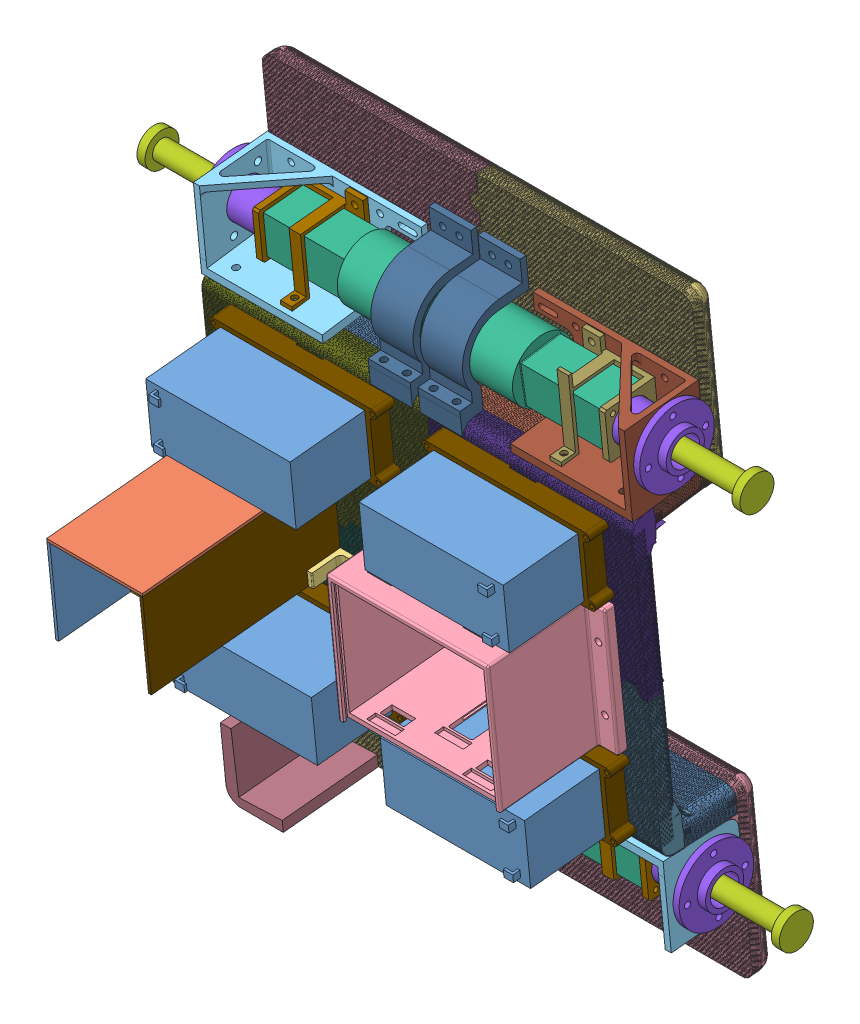
SolidWorks assembly A_B_C_subSplitParts_inserts, configuration Default. Lengths in mm.
Overall size (631 668.02 349.01).
106 component instances, 42 part files, 44 mates.
Components (placement in the parent):
- B_neo_texture_complete_55mm_1of2-1: B_neo_texture_complete_55mm_1of2 [Default] at (-505.8627 63.1056 254.1155) x (1 0 0) z (0 0.998921 0.046441) size (219.85 54.89 24)
- B_neo_texture_complete_55mm_2of2-1: B_neo_texture_complete_55mm_2of2 [Default] at (-505.8627 63.1056 254.1155) x (1 0 0) z (0 0.998921 0.046441) size (236.08 54.89 24)
- A_neo_part1-1: A_neo_part1 [Default] at (-291.5394 190.3641 320.5443) x (0 0.995122 0.098657) z (0 0.098657 -0.995122) size (187.3 234.72 36.32)
- A_neo_part1_inserts-1: A_neo_part1_inserts [Default] at (-174.6404 16.2028 208.0467) x (0 0.995122 0.098657) z (0 0.098657 -0.995122) size (187.33 225.47 36.32)
- assemblage moteur_simplifie-braquette-sol_sansPlancher-1: assemblage moteur_simplifie-braquette-sol_sansPlancher [Default] at (-882.4169 176.9564 -106.1681) x (0 0.995122 0.098657) z (1 0 0) size (163.91 86.22 311.5)
  - braquette bleu-1: braquette bleu [Default] at (-188.5719 315.838 826.9542) x (0 0 -1) z (1 0 0) size (205.75 78 138.28)
  - assemblage_moteur_pla_simplifie-1: assemblage_moteur_pla_simplifie [Default] at (-199.7546 211.4142 762.3925) x (0 0 1) z (0 1 0) size (311.5 78.45 78.45)
    - moteur_pla_simplifie-2: moteur_pla_simplifie [Default] at (-156.9384 51.1827 137.4238) size (176.5 64 64)
    - moteur_axe_pla_simplifie-1: moteur_axe_pla_simplifie [Default] at (3.5616 51.1827 137.4238) size (151 35.5 35.5)
    - front_housing_moteur_pla_simplifie-2: front_housing_moteur_pla_simplifie [Default] at (64.5616 51.1827 137.4238) x (1 0 0) z (0 0.00581 0.999983) size (60 78 78)
  - braquette gearbox-1: braquette gearbox [Default] at (-173.6322 327.188 785.9741) x (-0.000012 0 -1) z (0 -1 0) size (72.34 80.66 66.5)
  - braquette moteur- v2-1: braquette moteur- v2 [Default] at (-148.5686 348.838 605.4542) x (-1 0 0) z (0 0 -1) size (123.62 80 44)
- assemblage moteur_simplifie-braquette-sol_sansPlancher_Miroir-1: assemblage moteur_simplifie-braquette-sol_sansPlancher_Miroir [Default] at (510.9929 32.8996 -148.689) x (0 -0.99863 -0.052336) z (-1 0 0) size (180.67 88.54 311.5)
  - assemblage_moteur_pla_simplifie-1: assemblage_moteur_pla_simplifie [Default] at (-32.6554 239.0613 952.694) x (0 0 1) z (0 1 0) size (311.5 78.45 78.45)
    - moteur_pla_simplifie-2: moteur_pla_simplifie [Default] at (-156.9384 51.1827 137.4238) size (176.5 64 64)
    - moteur_axe_pla_simplifie-1: moteur_axe_pla_simplifie [Default] at (3.5616 51.1827 137.4238) size (151 35.5 35.5)
    - front_housing_moteur_pla_simplifie-2: front_housing_moteur_pla_simplifie [Default] at (64.5616 51.1827 137.4238) x (1 0 0) z (0 0.00581 0.999983) size (60 78 78)
  - braquette moteur- v2-1: braquette moteur- v2 [Default] at (18.5239 376.4853 839.7557) x (0.99917 -0.04074 0) z (0 0 1) size (123.62 80 44)
  - braquette bleue_mirroir-1: braquette bleue_mirroir [Default] at (56.9516 341.6631 1017.2557) x (0 0 -1) z (0.998921 -0.046441 0) size (167 78 87.38)
  - braquette gearbox_miroir_sansRef-1: braquette gearbox_miroir_sansRef [Default] at (70.4037 352.3999 976.2757) x (0 0 -1) z (-0.046441 -0.998921 0) size (72.34 158.52 66.5)
- Part1^A_B_C_subSplitParts_inserts-1: Part1^A_B_C_subSplitParts_inserts [Default] at (-291.5394 201.016 213.1012) x (0 -0.995122 -0.098657) z (0 -0.098657 0.995122) size (74.3 58.51 100) (virtual)
- C_assy_half_fix_part2of4-1: C_assy_half_fix_part2of4 [Default] at (-291.6733 128.4726 271.3664) x (0 0.995122 0.098657) z (1 0 0) size (163.15 37.28 239.16)
- C_assy_half_fix_part1of4-1: C_assy_half_fix_part1of4 [Default] at (-291.6733 128.2733 271.3467) x (0 0.995122 0.098657) z (1 0 0) size (163.15 37.29 220.95)
- C_assy_fix_half_hexCut_3of4-2: C_assy_fix_half_hexCut_3of4 [Default] at (-446.4822 196.3733 300.9272) x (0 -0.995122 -0.098657) z (-1 0 0) size (172.5 37.28 239.16)
- C_assy_fix_half_hexCut_4of4-2: C_assy_fix_half_hexCut_4of4 [Default] at (-446.4822 196.5726 300.947) x (0 -0.995122 -0.098657) z (-1 0 0) size (172.46 37.29 224.83)
- Position Insert_SIMPLIF-1: Position Insert_SIMPLIF [Default] at (-832.86 42.1169 -91.7262) x (0 0.995122 0.098657) z (1 0 0) size (658.2 305 450)
  - Plancher simple-1: Plancher simple [Default] at (193.6815 341.9451 552.3973) size (658.2 105 450) (hidden)
  - Battery Assy-1: Battery Assy [Default] at (10.1853 290.8701 314.8593) size (75 116 175)
    - Battery Holder-1: Battery Holder [Default] at (70.7211 76.075 126.038) size (75 20 175)
    - CANBAT CL19-12-1: CANBAT CL19-12 [Default] at (38.2211 127.075 126.038) x (0 0 1) z (-1 0 0) size (151 102.5 65)
    - M4 x 10 insert-1: M4 x 10 insert [Default] at (37.7211 66.075 209.038) x (1 0 0) z (0 1 0) size (5.88 5.88 10)
    - M4 x 10 insert-2: M4 x 10 insert [Default] at (103.7211 66.075 209.038) x (0.982082 0 -0.188455) z (0 1 0) size (5.88 5.88 10)
    - M4 x 10 insert-4: M4 x 10 insert [Default] at (37.7211 66.075 43.038) x (0.918365 0 -0.395734) z (0 1 0) size (5.88 5.88 10)
    - M4 x 10 insert-6: M4 x 10 insert [Default] at (103.7211 66.075 43.038) x (0.8 0 -0.6) z (0 1 0) size (5.88 5.88 10)
  - Battery Assy-2: Battery Assy [Default] at (235.7356 290.8701 314.8593) size (75 116 175)
    - Battery Holder-1: Battery Holder [Default] at (70.7211 76.075 126.038) size (75 20 175)
    - CANBAT CL19-12-1: CANBAT CL19-12 [Default] at (38.2211 127.075 126.038) x (0 0 1) z (-1 0 0) size (151 102.5 65)
    - M4 x 10 insert-1: M4 x 10 insert [Default] at (37.7211 66.075 209.038) x (1 0 0) z (0 1 0) size (5.88 5.88 10)
    - M4 x 10 insert-2: M4 x 10 insert [Default] at (103.7211 66.075 209.038) x (0.982082 0 -0.188455) z (0 1 0) size (5.88 5.88 10)
    - M4 x 10 insert-4: M4 x 10 insert [Default] at (37.7211 66.075 43.038) x (0.918365 0 -0.395734) z (0 1 0) size (5.88 5.88 10)
    - M4 x 10 insert-6: M4 x 10 insert [Default] at (103.7211 66.075 43.038) x (0.8 0 -0.6) z (0 1 0) size (5.88 5.88 10)
  - Battery Assy-4: Battery Assy [Default] at (151.6274 290.8701 789.9352) x (-1 0 0) z (0 0 -1) size (75 116 175)
    - Battery Holder-1: Battery Holder [Default] at (70.7211 76.075 126.038) size (75 20 175)
    - CANBAT CL19-12-1: CANBAT CL19-12 [Default] at (38.2211 127.075 126.038) x (0 0 1) z (-1 0 0) size (151 102.5 65)
    - M4 x 10 insert-1: M4 x 10 insert [Default] at (37.7211 66.075 209.038) x (1 0 0) z (0 1 0) size (5.88 5.88 10)
    - M4 x 10 insert-2: M4 x 10 insert [Default] at (103.7211 66.075 209.038) x (0.982082 0 -0.188455) z (0 1 0) size (5.88 5.88 10)
    - M4 x 10 insert-4: M4 x 10 insert [Default] at (37.7211 66.075 43.038) x (0.918365 0 -0.395734) z (0 1 0) size (5.88 5.88 10)
    - M4 x 10 insert-6: M4 x 10 insert [Default] at (103.7211 66.075 43.038) x (0.8 0 -0.6) z (0 1 0) size (5.88 5.88 10)
  - Earth Model v10.step-1: Earth Model v10.step [Default] at (146.6815 366.9451 356.3973) x (0 0 1) z (-1 0 0) size (100 200 100)
    - LED Mount.step-1: LED Mount.step [Default] at (12.6137 5.8766 -56) x (-1 0 0) z (0 0 1) size (22.02 4.05 21.78)
      - M1050D1-Step.step-1: M1050D1-Step.step [Default] at (0 -0.9747 1.4266) x (1 0 0) z (0 1 0) size (22.02 21.78 4.05)
      - LED Mount-0.step-1: LED Mount-0.step [Default] at origin size (4 1.45 12.5)
      - LED Mount-1.step-1: LED Mount-1.step [Default] at origin size (4 1.45 12.5)
    - LED Mount_1.step-1: LED Mount_1.step [Default] at (25.4909 5.8766 -37.0252) x (0.026177 0 0.999657) z (0.999657 0 -0.026177) size (22.02 4.05 21.78)
      - M1050D1-Step.step-1: M1050D1-Step.step [Default] at (0 -0.9747 1.4266) x (1 0 0) z (0 1 0) size (22.02 21.78 4.05)
      - LED Mount_1-2.step-1: LED Mount_1-2.step [Default] at origin size (4 1.45 12.5)
      - LED Mount_1-3.step-1: LED Mount_1-3.step [Default] at origin size (4 1.45 12.5)
    - LED Mount_2.step-1: LED Mount_2.step [Default] at (34.1545 5.8766 -58.9103) x (-0.707107 0 0.707107) z (0.707107 0 0.707107) size (22.02 4.05 21.78)
      - M1050D1-Step.step-1: M1050D1-Step.step [Default] at (0 -0.9747 1.4266) x (1 0 0) z (0 1 0) size (22.02 21.78 4.05)
      - LED Mount_2-4.step-1: LED Mount_2-4.step [Default] at origin size (4 1.45 12.5)
      - LED Mount_2-5.step-1: LED Mount_2-5.step [Default] at origin size (4 1.45 12.5)
    - Grating Attachment.step-1: Grating Attachment.step [Default] at (35 35 -51.5674) x (0 0 -1) z (1 0 0) size (36 29 36)
      - GR25-0613-Step.step-1: GR25-0613-Step.step [Default] at (2.9396 9.8961 -6.6872) x (0 0 1) z (-1 0 0) size (25 25 6)
      - Grating Attachment-6.step-1: Grating Attachment-6.step [Default] at origin size (36 29 36)
    - Circular Mirror Attachment.step-1: Circular Mirror Attachment.step [Default] at (13.9019 0.5 -80.0633) size (27 6.5 27)
    - CUI_DEVICES_CP60440.step-1: CUI_DEVICES_CP60440.step [Default] at (24.534 6.8513 -45.9559) x (0 0 -1) z (0 1 0) size (40 80 4)
    - Heat Sink - Earth Model.step-1: Heat Sink - Earth Model.step [Default] at (-4 -6.0386 -98) size (40 20 40)
    - Motor Mount.step-1: Motor Mount.step [Default] at (37 75.5 -53.05) x (0 0 1) z (-1 0 0) size (36.05 49 46)
    - Motor Spacer.step-1: Motor Spacer.step [Default] at (0 75.5 0) x (1 0 0) z (0 1 0) size (46 20 49)
    - Earth Model Good Copy Remake.step-1: Earth Model Good Copy Remake.step [Default] at origin size (94 3 94)
    - Earth Model Good Copy Remake-7.step-1: Earth Model Good Copy Remake-7.step [Default] at origin size (3 200 94)
    - Earth Model Good Copy Remake-8.step-1: Earth Model Good Copy Remake-8.step [Default] at origin size (3 200 94)
    - Earth Model Good Copy Remake-9.step-1: Earth Model Good Copy Remake-9.step [Default] at origin size (100 200 3)
    - Earth Model Good Copy Remake-10.step-1: Earth Model Good Copy Remake-10.step [Default] at origin size (100 200 3) (hidden)
  - L bracket-1: L bracket [Default] at (240.6815 366.9451 453.3973) x (0 0 1) z (-1 0 0) size (20 35 15)
  - L bracket-3: L bracket [Default] at (143.6815 366.9451 410.8973) x (-1 0 0) z (0 0 -1) size (20 35 15)
  - L bracket-5: L bracket [Default] at (243.6815 366.9451 395.8973) size (20 35 15)
  - 12220118_ELECTRICAL_BOX-1: 12220118_ELECTRICAL_BOX [Default] at (214.1224 366.9451 730.0206) x (0 0 -1) z (1 0 0) size (210 112.5 140)
  - Battery Assy-7: Battery Assy [Default] at (377.1777 290.8701 789.9352) x (-1 0 0) z (0 0 -1) size (75 116 175)
    - Battery Holder-1: Battery Holder [Default] at (70.7211 76.075 126.038) size (75 20 175)
    - CANBAT CL19-12-1: CANBAT CL19-12 [Default] at (38.2211 127.075 126.038) x (0 0 1) z (-1 0 0) size (151 102.5 65)
    - M4 x 10 insert-1: M4 x 10 insert [Default] at (37.7211 66.075 209.038) x (1 0 0) z (0 1 0) size (5.88 5.88 10)
    - M4 x 10 insert-2: M4 x 10 insert [Default] at (103.7211 66.075 209.038) x (0.982082 0 -0.188455) z (0 1 0) size (5.88 5.88 10)
    - M4 x 10 insert-4: M4 x 10 insert [Default] at (37.7211 66.075 43.038) x (0.918365 0 -0.395734) z (0 1 0) size (5.88 5.88 10)
    - M4 x 10 insert-6: M4 x 10 insert [Default] at (103.7211 66.075 43.038) x (0.8 0 -0.6) z (0 1 0) size (5.88 5.88 10)
  - L bracket-7: L bracket [Default] at (161.6815 366.9451 453.3973) x (0 0 1) z (-1 0 0) size (20 35 15)
- B_neo_texture_complete_55mm_2of2-2: B_neo_texture_complete_55mm_2of2 [Default] at (-55.8628 340.0504 281.614) x (-1 0 0) z (0 -0.988594 -0.150602) size (236.08 54.89 24)
- B_neo_texture_complete_55mm_1of2-2: B_neo_texture_complete_55mm_1of2 [Default] at (-55.8628 340.0504 281.614) x (-1 0 0) z (0 -0.988594 -0.150602) size (219.85 54.89 24)
- assemblage moteur_simplifie-braquette-sol_sansPlancher_Miroir-2: assemblage moteur_simplifie-braquette-sol_sansPlancher_Miroir [Default] at (-1072.5185 448.7658 -107.4598) x (0 0.989466 0.144765) z (1 0 0) size (180.67 88.54 311.5)
  - assemblage_moteur_pla_simplifie-1: assemblage_moteur_pla_simplifie [Default] at (-32.6554 239.0613 952.694) x (0 0 1) z (0 1 0) size (311.5 78.45 78.45)
    - moteur_pla_simplifie-2: moteur_pla_simplifie [Default] at (-156.9384 51.1827 137.4238) size (176.5 64 64)
    - moteur_axe_pla_simplifie-1: moteur_axe_pla_simplifie [Default] at (3.5616 51.1827 137.4238) size (151 35.5 35.5)
    - front_housing_moteur_pla_simplifie-2: front_housing_moteur_pla_simplifie [Default] at (64.5616 51.1827 137.4238) x (1 0 0) z (0 0.00581 0.999983) size (60 78 78)
  - braquette moteur- v2-1: braquette moteur- v2 [Default] at (18.5239 376.4853 839.7557) x (0.99917 -0.04074 0) z (0 0 1) size (123.62 80 44)
  - braquette bleue_mirroir-1: braquette bleue_mirroir [Default] at (56.9516 341.6631 1017.2557) x (0 0 -1) z (0.998921 -0.046441 0) size (167 78 87.38)
  - braquette gearbox_miroir_sansRef-1: braquette gearbox_miroir_sansRef [Default] at (70.4037 352.3999 976.2757) x (0 0 -1) z (-0.046441 -0.998921 0) size (72.34 158.52 66.5)
- assemblage moteur_simplifie-braquette-sol_sansPlancher-2: assemblage moteur_simplifie-braquette-sol_sansPlancher [Default] at (320.8913 299.1642 -94.0523) x (0 -0.995122 -0.098657) z (-1 0 0) size (163.91 86.22 311.5)
  - braquette bleu-1: braquette bleu [Default] at (-188.5719 315.838 826.9542) x (0 0 -1) z (1 0 0) size (205.75 78 138.28)
  - assemblage_moteur_pla_simplifie-1: assemblage_moteur_pla_simplifie [Default] at (-199.7546 211.4142 762.3925) x (0 0 1) z (0 1 0) size (311.5 78.45 78.45)
    - moteur_pla_simplifie-2: moteur_pla_simplifie [Default] at (-156.9384 51.1827 137.4238) size (176.5 64 64)
    - moteur_axe_pla_simplifie-1: moteur_axe_pla_simplifie [Default] at (3.5616 51.1827 137.4238) size (151 35.5 35.5)
    - front_housing_moteur_pla_simplifie-2: front_housing_moteur_pla_simplifie [Default] at (64.5616 51.1827 137.4238) x (1 0 0) z (0 0.00581 0.999983) size (60 78 78)
  - braquette gearbox-1: braquette gearbox [Default] at (-173.6322 327.188 785.9741) x (-0.000012 0 -1) z (0 -1 0) size (72.34 80.66 66.5)
  - braquette moteur- v2-1: braquette moteur- v2 [Default] at (-148.5686 348.838 605.4542) x (-1 0 0) z (0 0 -1) size (123.62 80 44)
- A_neo_part1_inserts-3: A_neo_part1_inserts [Default] at (-386.8852 394.295 245.531) x (0 -0.995122 -0.098657) z (0 0.098657 -0.995122) size (187.33 225.47 36.32)
- A_neo_part1-3: A_neo_part1 [Default] at (-269.9862 201.435 321.6418) x (0 -0.995122 -0.098657) z (0 0.098657 -0.995122) size (187.3 234.72 36.32)
Mates (geometry in assembly coordinates):
- Coincident9: coincident anti-aligned: line of B_neo_texture_complete_55mm_1of2-1 through (-275.3064 40.793 234.4892) axis (0 -0.046441 0.998921); line of B_neo_texture_complete_55mm_2of2-1 through (-275.3064 39.9306 253.038) axis (0 0.046441 -0.998921)
- Coincident12: coincident anti-aligned: line of B_neo_texture_complete_55mm_1of2-1 through (-275.3064 39.9306 253.038) axis (0 0.998921 0.046441); line of B_neo_texture_complete_55mm_2of2-1 through (-275.3064 48.4215 253.4328) axis (0 -0.998921 -0.046441)
- Distance3: distance = 0.5 mm: line of assemblage moteur_simplifie-braquette-sol_sansPlancher-1/braquette bleu-1 through (-182.4627 41.0469 209.6481) axis (1 0 0); plane of B_neo_texture_complete_55mm_1of2-1 through (-57.6627 39.5017 253.6512) normal (0 -0.998921 -0.046441)
- Coincident24: coincident aligned: line of A_neo_part1-1 through (-280.8627 -101.8983 182.6682) axis (0 0.098657 -0.995122); line of A_neo_part1_inserts-1 through (-280.8627 -101.8983 182.6682) axis (0 0.098657 -0.995122)
- Coincident25: coincident aligned: plane of A_neo_part1-1 through (-282.6627 -132.115 180.0744) normal (0 -0.098657 0.995122); plane of A_neo_part1_inserts-1 through (-279.0627 -132.115 180.0744) normal (0 -0.098657 0.995122)
- Coincident26: coincident anti-aligned: plane of B_neo_texture_complete_55mm_1of2-1 through (-55.8627 50.9706 198.602) normal (0 0.046441 -0.998921); plane of A_neo_part1_inserts-1 through (-505.8627 51.1704 198.6113) normal (0 -0.046441 0.998921)
- Distance4: distance = 0.2 mm anti-aligned: plane of B_neo_texture_complete_55mm_1of2-1 through (-55.8627 50.5991 206.5934) normal (0 0.998921 0.046441); plane of A_neo_part1_inserts-1 through (-505.8627 50.8453 205.6037) normal (0 -0.998921 -0.046441)
- Coincident28: coincident: line of B_neo_texture_complete_55mm_1of2-1 through (-55.4627 45.924 253.3167) axis (0 0.046441 -0.998921); plane of A_neo_part1_inserts-1 through (-55.4627 53.5695 194.4636) normal (1 0 0)
- Distance5: distance = 0.5 mm anti-aligned: plane of A_neo_part1_inserts-1 through (-57.6627 -132.115 180.0744) normal (0 -0.098657 0.995122); plane of assemblage moteur_simplifie-braquette-sol_sansPlancher-1/braquette bleu-1 through (-55.4627 37.7546 197.4178) normal (0 0.098657 -0.995122)
- Coincident30: coincident aligned: plane of A_neo_part1_inserts-1 through (-55.4627 53.8654 191.4783) normal (1 0 0); plane of assemblage moteur_simplifie-braquette-sol_sansPlancher-1/braquette bleu-1 through (-55.4627 37.7546 197.4178) normal (1 0 0)
- Coincident31: coincident aligned: plane of A_neo_part1-1 through (-506.2627 54.1614 188.4929) normal (-1 0 0); plane of assemblage moteur_simplifie-braquette-sol_sansPlancher_Miroir-1/braquette bleue_mirroir-1 through (-506.2627 -121.4649 181.6327) normal (-1 0 0)
- Distance6: distance = 0.5 mm anti-aligned: plane of assemblage moteur_simplifie-braquette-sol_sansPlancher_Miroir-1/braquette bleue_mirroir-1 through (-506.2627 -121.4649 181.6327) normal (0 0.098657 -0.995122); plane of A_neo_part1-1 through (-444.6627 -132.115 180.0744) normal (0 -0.098657 0.995122)
- Distance7: distance = 0.5 mm anti-aligned: plane of B_neo_texture_complete_55mm_2of2-1 through (-498.6627 39.5017 253.6512) normal (0 -0.998921 -0.046441); plane of assemblage moteur_simplifie-braquette-sol_sansPlancher_Miroir-1/braquette bleue_mirroir-1 through (-420.4101 38.4724 265.025) normal (0 0.998921 0.046441)
- InPlace1: in place: plane of ? through (-359.2355 -15.3034 200.0451) normal (0 -0.098657 0.995122); plane of ? through (0 -19.7885 199.6005) normal (0 -0.098657 0.995122); moOrthogonalPlaneRef_w of ? through (-359.2355 -15.3034 200.0451) normal (0 -0.098657 0.995122); plane of ? through (0 -19.7885 199.6005) normal (0 0.995122 0.098657); plane of ? through (-359.2355 -15.3034 200.0451) normal (0 -0.098657 0.995122); plane of ? through (0 -19.7885 199.6005) normal (1 0 0); plane of A_neo_part1-1 through (-500.4627 -132.115 180.0744) normal (0 -0.098657 0.995122); unknown of Part1^A_B_C_subSplitParts_inserts-1
- Coincident32: coincident aligned: plane of A_neo_part1-1; plane of Part1^A_B_C_subSplitParts_inserts-1
- Coincident33: coincident aligned: moOrthogonalPlaneRef_w of A_neo_part1-1 through (-291.5394 201.016 213.1012) normal (1 0 0); plane of Part1^A_B_C_subSplitParts_inserts-1 through (-291.5394 201.016 213.1012) normal (1 0 0)
- Coincident34: coincident anti-aligned: moOrthogonalPlaneRef_w of A_neo_part1-1 through (-291.5394 201.016 213.1012) normal (0 0.995122 0.098657); plane of Part1^A_B_C_subSplitParts_inserts-1 through (-291.5394 201.016 213.1012) normal (0 -0.995122 -0.098657)
- Coincident32: coincident anti-aligned: plane of B_neo_texture_complete_55mm_2of2-1 through (-55.8627 39.9306 253.038) normal (0 -0.046441 0.998921); plane of C_assy_half_fix_part2of4-1 through (-67.8627 39.0316 252.9962) normal (0 0.046441 -0.998921)
- Coincident33: coincident aligned: plane of B_neo_texture_complete_55mm_1of2-1 through (-55.8627 63.1056 254.1155) normal (1 0 0); plane of C_assy_half_fix_part2of4-1 through (-55.8627 39.0316 252.9962) normal (1 0 0)
- Distance8: distance = 0.2 mm anti-aligned: plane of B_neo_texture_complete_55mm_1of2-1 through (-55.8627 48.4215 253.4328) normal (0 0.998921 0.046441); plane of C_assy_half_fix_part2of4-1 through (-16.7922 48.6212 253.4421) normal (0 -0.998921 -0.046441)
- Coincident35: coincident anti-aligned: plane of C_assy_half_fix_part2of4-1 through (-291.4952 128.4726 271.3664) normal (-1 0 0); plane of C_assy_half_fix_part1of4-1 through (-291.4952 74.579 229.991) normal (1 0 0)
- Coincident36: coincident anti-aligned: plane of B_neo_texture_complete_55mm_2of2-1 through (-55.8627 48.4215 253.4328) normal (0 0.998921 0.046441); plane of C_assy_half_fix_part1of4-1 through (-16.7922 48.4219 253.4223) normal (0 -0.998921 -0.046441)
- Coincident37: coincident aligned: plane of C_assy_half_fix_part2of4-1 through (-55.2627 74.5392 280.2322) normal (0 -0.098657 0.995122); plane of C_assy_half_fix_part1of4-1 through (-55.2627 83.2951 281.1002) normal (0 -0.098657 0.995122)
- Coincident38: coincident aligned: line of C_assy_half_fix_part2of4-1 through (-67.2431 201.043 269.2119) axis (0 -0.098657 0.995122); line of C_assy_fix_half_hexCut_4of4-2 through (-67.2431 201.043 269.212) axis (0 -0.098657 0.995122)
- Coincident39: coincident aligned: plane of C_assy_half_fix_part2of4-1 through (-55.2627 187.386 291.4199) normal (0 -0.098657 0.995122); plane of C_assy_fix_half_hexCut_4of4-2 through (-506.4628 210.0737 293.6691) normal (0 -0.098657 0.995122)
- Coincident40: coincident aligned: line of C_assy_half_fix_part1of4-1 through (-494.4824 200.8437 269.1922) axis (0 -0.098657 0.995122); line of C_assy_fix_half_hexCut_3of4-2 through (-494.4824 200.8437 269.1922) axis (0 -0.098657 0.995122)
- Coincident41: coincident aligned: plane of C_assy_half_fix_part1of4-1 through (-55.2627 187.1867 291.4001) normal (0 -0.098657 0.995122); plane of C_assy_fix_half_hexCut_3of4-2 through (-295.5731 196.3911 292.3126) normal (0 -0.098657 0.995122)
- Coincident42: coincident aligned: plane of C_assy_half_fix_part2of4-1 through (-55.2627 56.6262 278.4563) normal (0 -0.098657 0.995122); plane of Position Insert_SIMPLIF-1/Plancher simple-1 through (-505.4627 50.7551 277.8742) normal (0 -0.098657 0.995122)
- Coincident43: coincident aligned: plane of C_assy_half_fix_part2of4-1 through (-55.4627 50.6738 275.655) normal (1 0 0); plane of Position Insert_SIMPLIF-1/Plancher simple-1 through (-55.4627 28.6896 207.8557) normal (1 0 0)
- Coincident44: coincident anti-aligned: line of B_neo_texture_complete_55mm_2of2-2 through (-286.4192 362.9858 285.1079) axis (0 0.150602 -0.988594); line of B_neo_texture_complete_55mm_1of2-2 through (-286.4192 365.7823 266.7509) axis (0 -0.150602 0.988594)
- Coincident45: coincident anti-aligned: line of B_neo_texture_complete_55mm_2of2-2 through (-286.4192 354.5828 283.8278) axis (0 0.988594 0.150602); line of B_neo_texture_complete_55mm_1of2-2 through (-286.4192 362.9858 285.1079) axis (0 -0.988594 -0.150602)
- Coincident50: coincident anti-aligned: plane of C_assy_fix_half_hexCut_4of4-2 through (-544.9334 348.6512 282.9242) normal (0 0.150602 -0.988594); plane of B_neo_texture_complete_55mm_2of2-2 through (-505.8628 348.4535 282.8941) normal (0 -0.150602 0.988594)
- Coincident51: coincident aligned: plane of C_assy_fix_half_hexCut_4of4-2 through (-55.8628 348.2538 293.5007) normal (1 0 0); plane of B_neo_texture_complete_55mm_2of2-2 through (-55.8628 340.0504 281.614) normal (1 0 0)
- Distance11: distance = 0.2 mm anti-aligned: plane of B_neo_texture_complete_55mm_2of2-2 through (-505.8628 349.6583 274.9853) normal (0 0.988594 0.150602); plane of C_assy_fix_half_hexCut_4of4-2 through (-544.9334 349.7054 276.0041) normal (0 -0.988594 -0.150602)
- Distance13: distance = 0.5 mm anti-aligned: plane of A_neo_part1_inserts-3 through (-503.8628 545.218 247.2255) normal (0 -0.098657 0.995122); plane of assemblage moteur_simplifie-braquette-sol_sansPlancher-2/braquette bleu-1 through (-506.0628 376.0469 230.9563) normal (0 0.098657 -0.995122)
- Coincident54: coincident aligned: plane of assemblage moteur_simplifie-braquette-sol_sansPlancher_Miroir-2/braquette bleue_mirroir-1 through (-55.2628 535.2664 246.7413) normal (1 0 0); plane of A_neo_part1-3 through (-55.2628 360.9147 218.9046) normal (1 0 0)
- Coincident55: coincident aligned: line of A_neo_part1_inserts-3 through (-280.6628 515.0801 243.8357) axis (0 0.098657 -0.995122); line of A_neo_part1-3 through (-280.6628 515.0801 243.8357) axis (0 0.098657 -0.995122)
- Coincident56: coincident aligned: plane of assemblage moteur_simplifie-braquette-sol_sansPlancher-2/braquette bleu-1 through (-506.0628 376.0469 230.9563) normal (-1 0 0); plane of A_neo_part1_inserts-3 through (-506.0628 360.6187 221.8899) normal (-1 0 0)
- Coincident57: coincident aligned: plane of A_neo_part1_inserts-3 through (-282.4628 545.218 247.2255) normal (0 -0.098657 0.995122); plane of A_neo_part1-3 through (-278.8628 545.218 247.2255) normal (0 -0.098657 0.995122)
- Coincident59: coincident anti-aligned: plane of A_neo_part1_inserts-3 through (-280.6628 352.6771 257.882) normal (1 0 0); plane of A_neo_part1-3 through (-280.6628 362.3215 268.8872) normal (-1 0 0)
- Coincident60: coincident aligned: line of B_neo_texture_complete_55mm_2of2-2 through (-55.6628 360.3778 229.1874) axis (0 0.988594 0.150602); line of A_neo_part1-3 through (-55.6628 361.8607 229.4133) axis (0 0.988594 0.150602)
- Distance14: distance = 0.2 mm anti-aligned: plane of A_neo_part1-3 through (-55.6628 356.9178 228.6603) normal (0 -0.988594 -0.150602); plane of B_neo_texture_complete_55mm_2of2-2 through (-505.8628 356.72 228.6301) normal (0 0.988594 0.150602)
- Distance15: distance = 0.5 mm: plane of B_neo_texture_complete_55mm_2of2-2 through (-57.6628 363.286 285.7934) normal (0 0.988594 0.150602); line of assemblage moteur_simplifie-braquette-sol_sansPlancher_Miroir-2/braquette bleue_mirroir-1 through (-182.2628 370.4173 242.302) axis (1 0 0)
- Coincident64: coincident anti-aligned: line of assemblage moteur_simplifie-braquette-sol_sansPlancher_Miroir-2/braquette bleue_mirroir-1 through (-182.2628 370.4173 242.302) axis (1 0 0); line of assemblage moteur_simplifie-braquette-sol_sansPlancher-2/braquette bleu-1 through (-379.0628 370.4173 242.302) axis (-1 0 0)
